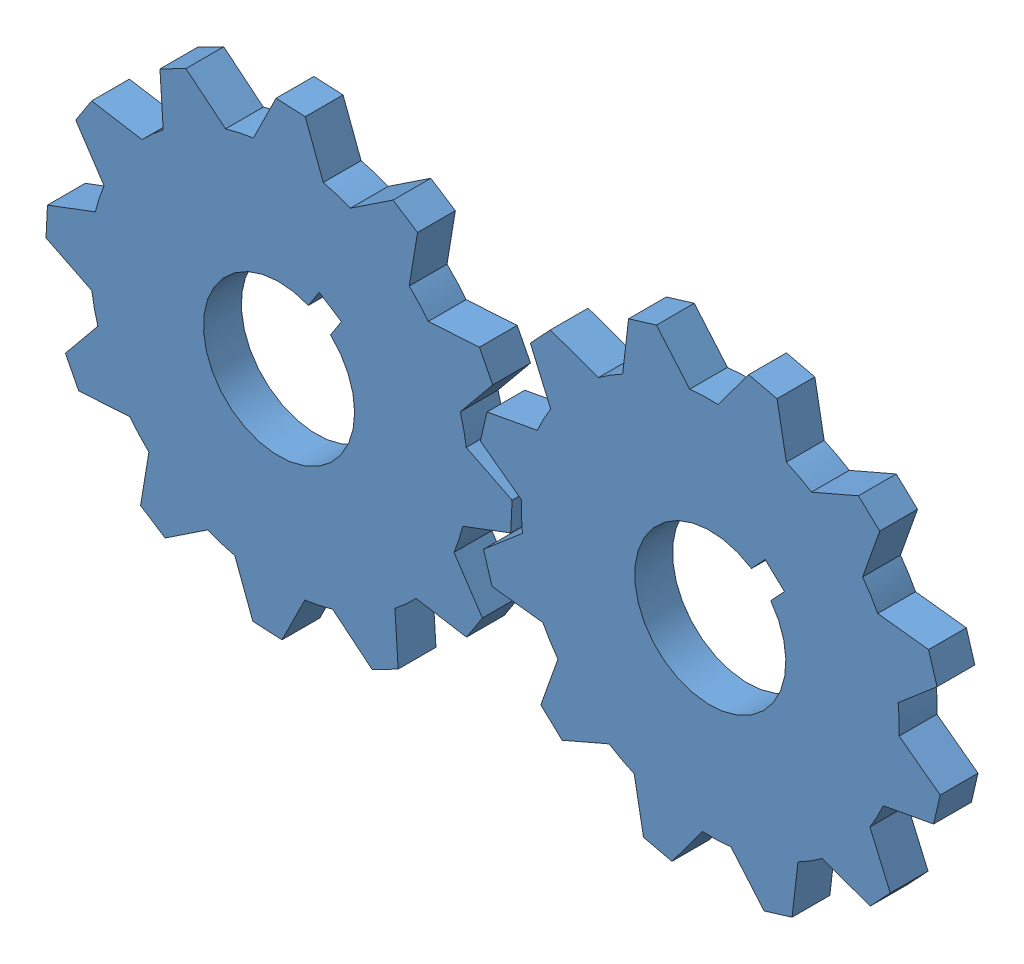
SolidWorks assembly Test_3, configuration Default. Lengths in mm.
Overall size (286.2 173.99 10).
2 component instances, 1 part files, 4 mates.
Components (placement in the parent):
- Gear_1-2: Gear_1 [Default] at (134.947 140.0371 0) x (-0.730712 0.682686 0) z (0 0 1) size (123.1 123.1 10)
- Gear_1-3: Gear_1 [Default] at (20.8416 140.0371 0) x (-0.839986 0.542608 0) z (0 0 1) size (123.1 123.1 10)
Mates (geometry in assembly coordinates):
- Concentric2: concentric anti-aligned: circle of Gear_1-3
- Concentric3: concentric anti-aligned: circle of Gear_1-2
- Coincident2: coincident anti-aligned: plane of Gear_1-3 through (20.8416 140.0371 0) normal (0 0 -1)
- Coincident3: coincident anti-aligned: plane of Gear_1-2 through (134.947 140.0371 0) normal (0 0 -1)
